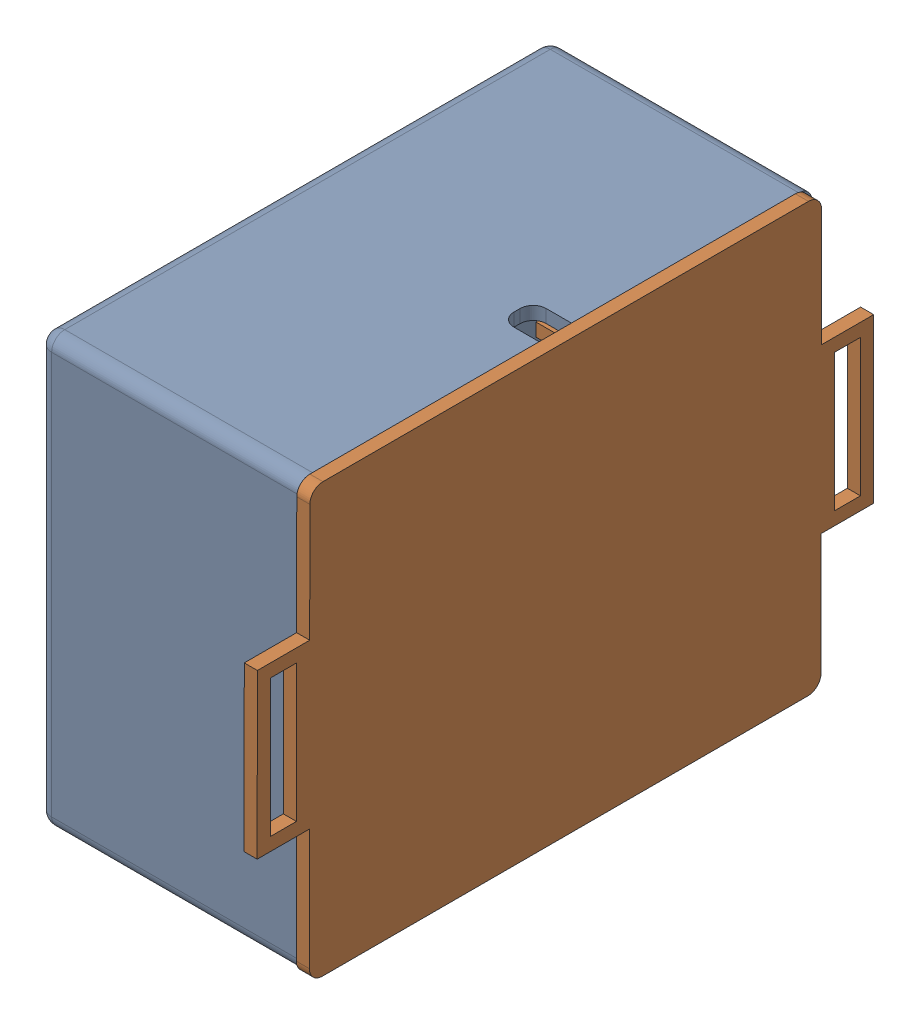
SolidWorks assembly FireBeetleD7, configuration Default. Lengths in mm.
Overall size (42 65.66 94.2).
2 component instances, 2 part files, 1 mates.
Components (placement in the parent):
- FireBeetleShellD7-1: FireBeetleShellD7 [Default] at (625.2315 861.8546 1310.7768) size (40 65.5 78.2)
- FireBeetleShellCapD7-1: FireBeetleShellCapD7 [Default] at (667.1985 857.9799 1294.4962) x (-0.001242 -0.999999 0) z (-0.999999 0.001242 0) size (65.5 94.2 7)
Mates (geometry in assembly coordinates):
- Coincident2: coincident anti-aligned: line of FireBeetleShellD7-1 through (665.2315 884.5708 1249.4185) axis (0 0 1); line of FireBeetleShellCapD7-1 through (665.2315 884.5708 1324.0101) axis (0 0 -1)
